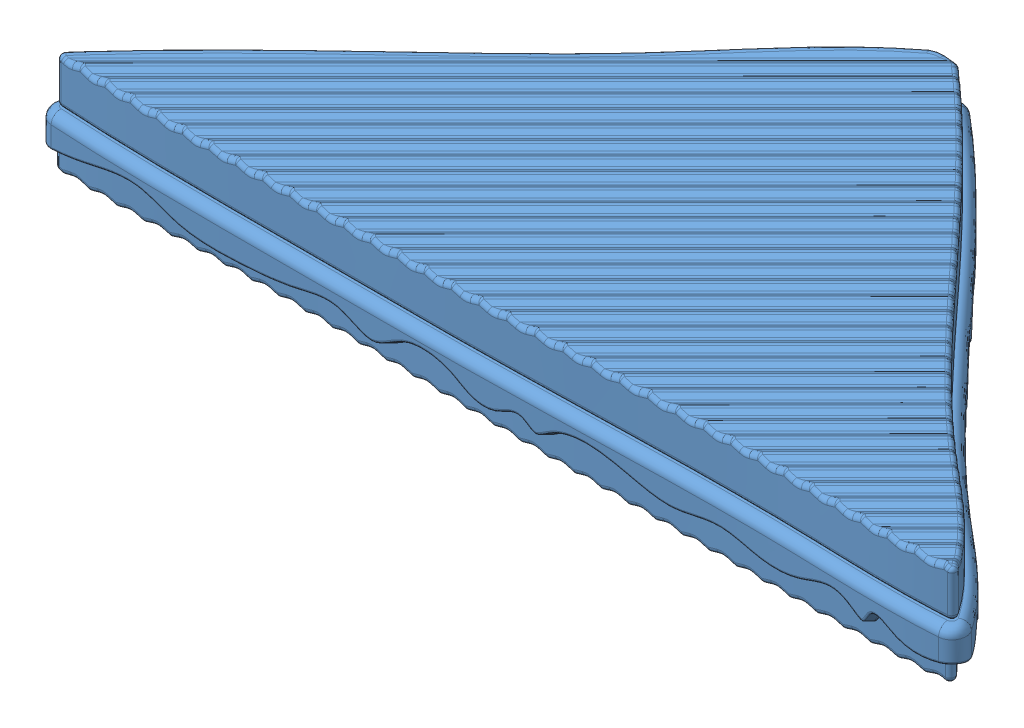
SolidWorks assembly Grilled Cheese, configuration Default. Lengths in mm.
Overall size (197.58 29.94 114.63).
2 component instances, 1 part files, 3 mates.
Components (placement in the parent):
- Grilled Cheese-1: Grilled Cheese [Default] at origin size (197.58 29.94 114.63)
- Grilled Cheese-2: Grilled Cheese [Bottom] at (0 -2 0) x (-1 0 0) z (0 0 1) size (188.07 19.76 99.88)
Mates (geometry in assembly coordinates):
- Coincident1: coincident anti-aligned: plane of Grilled Cheese-1 through (-0.4427 -2 2.8737) normal (0 -1 0); plane of Grilled Cheese-2 through (47.4142 -2 -47.4332) normal (0 1 0)
- Coincident2: coincident aligned: plane of Grilled Cheese-1 through (0 0 0) normal (0 0 1); plane of Grilled Cheese-2 through (0 -2 0) normal (0 0 1)
- Coincident3: coincident anti-aligned: plane of Grilled Cheese-1 through (0 0 0) normal (1 0 0); plane of Grilled Cheese-2 through (0 -2 0) normal (-1 0 0)
